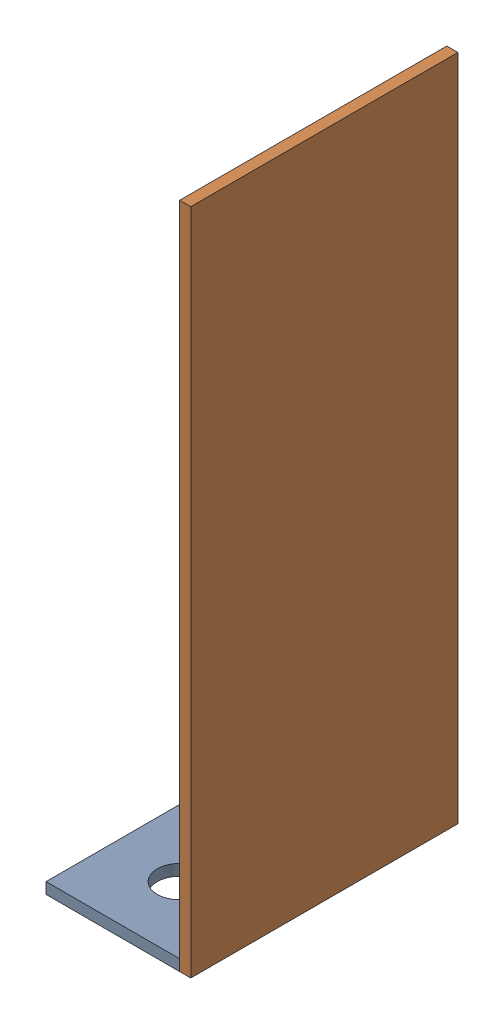
SolidWorks assembly 01-084-00-0, configuration Default. Lengths in mm.
Overall size (82.55 381 152.4).
3 component instances, 3 part files, 6 mates.
Components (placement in the parent):
- 01-083-00-0-1: 01-083-00-0 [Default] at (-41.8449 -4.93 79.3685) size (76.2 6.35 152.4)
- 01-081-00-0-1: 01-081-00-0 [Default] at (40.7051 -4.93 -73.0315) x (0 0 1) z (0 -1 0) size (152.4 6.35 381)
- 01-082-00-0-1: 01-082-00-0 [Default] at (-16.4449 1.42 -0.0065) x (1 0 0) z (0 -1 0) size (50.8 6.35 304.8)
Mates (geometry in assembly coordinates):
- Coincident1: coincident anti-aligned: plane of 01-083-00-0-1 through (34.3551 1.42 79.3685) normal (1 0 0); plane of 01-081-00-0-1 through (34.3551 376.07 -73.0315) normal (-1 0 0)
- Coincident2: coincident aligned: plane of 01-083-00-0-1 through (-41.8449 -4.93 -73.0315) normal (0 -1 0); plane of 01-081-00-0-1 through (34.3551 -4.93 -73.0315) normal (0 -1 0)
- Coincident3: coincident aligned: plane of 01-083-00-0-1 through (-41.8449 1.42 79.3685) normal (0 0 1); plane of 01-081-00-0-1 through (34.3551 -4.93 79.3685) normal (0 0 1)
- Coincident4: coincident anti-aligned: plane of 01-083-00-0-1 through (-41.8449 1.42 -73.0315) normal (0 1 0); plane of 01-082-00-0-1 through (-16.4449 1.42 6.3435) normal (0 -1 0)
- Coincident5: coincident: moEndPointRef_w of 01-083-00-0-1; moEndPointRef_w of 01-082-00-0-1
- Coincident6: coincident anti-aligned: plane of 01-081-00-0-1 through (34.3551 376.07 -73.0315) normal (-1 0 0); plane of 01-082-00-0-1 through (34.3551 1.42 6.3435) normal (1 0 0)
